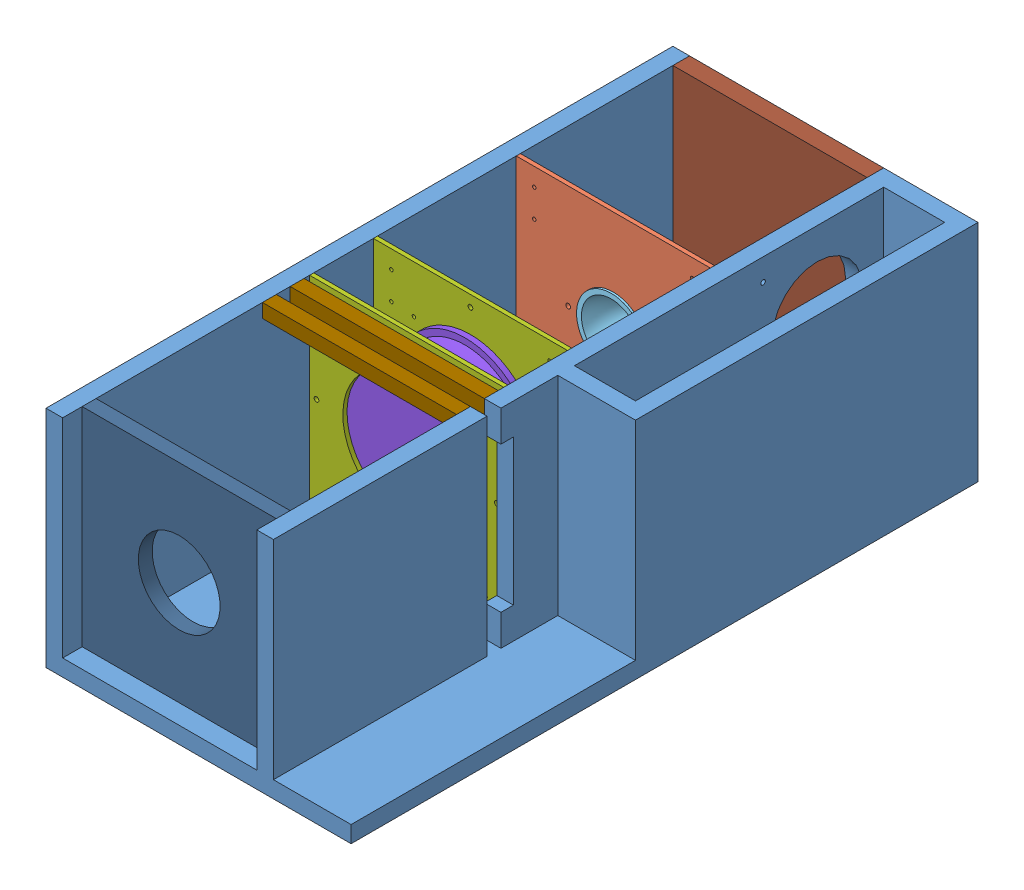
SolidWorks assembly assemble, configuration 默认. Lengths in mm.
Overall size (220 162 458.94).
20 component instances, 11 part files, 21 mates.
Components (placement in the parent):
- 底板^assemble-1: 底板^assemble [默认] x (1 0 0) z (0 1 0) size (220 452.06 162) (virtual)
- 光源总成^assemble-1: 光源总成^assemble [默认] at (-150.8348 91.7387 -154.1915) size (140 150 58.5) (virtual)
  - 前挡板^光源总成_assemble-1: 前挡板^光源总成_assemble [默认] at (150.8348 -91.7387 154.1915) x (1 0 0) z (0 1 0) size (140 3 150) (virtual)
  - 螺柱^光源总成_assemble-1: 螺柱^光源总成_assemble [默认] at (150.8348 -91.7387 -175.8665) x (1 0 0) z (0 0 -1) size (6 6 51) (virtual)
  - 螺柱^光源总成_assemble-2: 螺柱^光源总成_assemble [默认] at (331.8762 -54.5822 -175.8665) x (-0.652418 0.757859 0) z (0 0 -1) size (6 6 51) (virtual)
  - 灯座板^光源总成_assemble-2: 灯座板^光源总成_assemble [默认] at (150.8348 -91.7387 -226.8665) x (1 0 0) z (0 0 -1) size (71 17 3) (virtual)
  - MR16-1: MR16 [默认] at (232.8348 -16.7387 -211.0665) x (1 0 0) z (0 -1 0) size (50 39.7 50)
  - 角铁2020-1: 角铁2020 [默认] at (162.8348 20.2613 -175.8665) x (1 0 0) z (0 1 0) size (20 20 10)
- 聚光镜^assemble-2: 聚光镜^assemble [默认] at (-20.2075 11.0859 -179.938) size (140 150 49) (virtual)
  - 档板^聚光镜_assemble-1: 档板^聚光镜_assemble [默认] at (20.2075 -11.0859 179.938) x (1 0 0) z (0 1 0) size (140 3 150) (virtual)
  - flat_convex_lens-1: flat_convex_lens [默认] at (102.2075 63.9141 -44.12) x (0 0 1) z (-1 0 0) size (20.7 100 100)
  - 档板^聚光镜_assemble-2: 档板^聚光镜_assemble [默认] at (20.2075 -11.0859 225.938) x (1 0 0) z (0 1 0) size (140 3 150) (virtual)
  - flat_convex_lens-2: flat_convex_lens [默认] at (102.2075 63.9141 -1.12) x (0 0 -1) z (0.964741 -0.263202 0) size (20.7 100 100)
- 导槽^assemble-1: 导槽^assemble [默认] at (152 0 0) x (0 1 0) z (-1 0 0) size (10 10 140) (virtual)
- 导槽^assemble-3: 导槽^assemble [默认] at (152 0 -20) x (0 1 0) z (-1 0 0) size (10 10 140) (virtual)
- 导槽^assemble-4: 导槽^assemble [默认] at (152 -140 0) x (0 1 0) z (-1 0 0) size (10 10 140) (virtual)
- 导槽^assemble-5: 导槽^assemble [默认] at (152 -140 -20) x (0 1 0) z (-1 0 0) size (10 10 140) (virtual)
- 镜头板^assemble-2: 镜头板^assemble [默认] at origin size (140 150 10) (virtual)
  - 零件3^镜头板_assemble-1: 零件3^镜头板_assemble [默认] x (1 0 0) z (0 1 0) size (140 10 150) (virtual)
- 零件1^assemble-1: 零件1^assemble [默认] x (1 0 0) z (0 1 0) size (140 12 150) (virtual)
Mates (geometry in assembly coordinates):
- 在位1: in place: plane of ? through (0 0 0) normal (0 1 0); moOrthogonalPlaneRef_w of ? through (0 0 0) normal (0 0 -1); plane of ? through (0 0 0) normal (1 0 0); unknown of ?
- 重合1: coincident: plane of 底板^assemble-1; plane of assembly
- 重合2: coincident: plane of ? through (0 0 0) normal (0 0 -1)
- 重合3: coincident: plane of ? through (0 0 0) normal (1 0 0)
- 在位2: in place: plane of ? through (318.9073 150 -300) normal (-1 0 0); plane of ? through (318.9073 0 0) normal (-1 0 0); plane of ? through (318.9073 150 -300) normal (-1 0 0); plane of ? through (318.9073 0 0) normal (0 1 0); plane of ? through (318.9073 150 -300) normal (-1 0 0); plane of ? through (318.9073 0 0) normal (0 0 1); plane of ? through (152 150 -452.058) normal (-1 0 0); unknown of 导槽^assemble-1
- 重合1: coincident: plane of 底板^assemble-1; plane of 导槽^assemble-1
- 重合2: coincident: moOrthogonalPlaneRef_w of 底板^assemble-1 through (152 0 0) normal (0 0 -1); plane of 导槽^assemble-1 through (152 0 0) normal (0 0 -1)
- 重合3: coincident: moOrthogonalPlaneRef_w of 底板^assemble-1 through (152 0 0) normal (0 -1 0); plane of 导槽^assemble-1 through (152 0 0) normal (0 1 0)
- 重合4: coincident: plane of 底板^assemble-1 through (152 150 -452.058) normal (-1 0 0); plane of 导槽^assemble-3 through (152 0 -20) normal (1 0 0)
- 重合6: coincident: plane of 导槽^assemble-1 through (-2.1421 150 -154.058) normal (0 1 0); plane of 导槽^assemble-3 through (-2.1421 150 -174.058) normal (0 1 0)
- 距离1: distance = 10 mm: plane of 导槽^assemble-3 through (-2.1421 150 -164.058) normal (0 0 1); plane of 导槽^assemble-1 through (-2.1421 150 -154.058) normal (0 0 -1)
- 重合8: coincident: plane of 底板^assemble-1 through (152 150 -452.058) normal (-1 0 0); plane of 导槽^assemble-4 through (152 -140 0) normal (1 0 0)
- 重合9: coincident: plane of 底板^assemble-1 through (0 0 0) normal (0 1 0); plane of 导槽^assemble-4 through (-2.1421 0 -154.058) normal (0 -1 0)
- 重合10: coincident: plane of 导槽^assemble-1 through (-2.1421 150 -144.058) normal (0 0 1); plane of 导槽^assemble-4 through (-2.1421 10 -144.058) normal (0 0 1)
- 重合12: coincident: plane of 底板^assemble-1 through (0 0 0) normal (0 1 0); plane of 导槽^assemble-5 through (-2.1421 0 -174.058) normal (0 -1 0)
- 重合13: coincident: plane of 底板^assemble-1 through (152 150 -452.058) normal (-1 0 0); plane of 导槽^assemble-5 through (152 -140 -20) normal (1 0 0)
- 重合14: coincident: plane of 导槽^assemble-3 through (-2.1421 150 -164.058) normal (0 0 1); plane of 导槽^assemble-5 through (-2.1421 10 -164.058) normal (0 0 1)
- 在位3: in place: plane of ? through (0 0 0) normal (0 1 0); plane of ? through (0 0 0) normal (0 1 0); plane of ? through (0 0 0) normal (0 1 0); plane of ? through (0 0 0) normal (0 0 -1); plane of ? through (0 0 0) normal (0 1 0); plane of ? through (0 0 0) normal (1 0 0); plane of ? through (0 0 0) normal (0 1 0); unknown of ?
- 重合15: coincident: plane of 底板^assemble-1; plane of 零件1^assemble-1
- 重合16: coincident: moOrthogonalPlaneRef_w of 底板^assemble-1 through (0 0 0) normal (0 0 -1); plane of 零件1^assemble-1 through (0 0 0) normal (0 0 -1)
- 重合17: coincident: moOrthogonalPlaneRef_w of 底板^assemble-1 through (0 0 0) normal (-1 0 0); plane of 零件1^assemble-1 through (0 0 0) normal (1 0 0)
